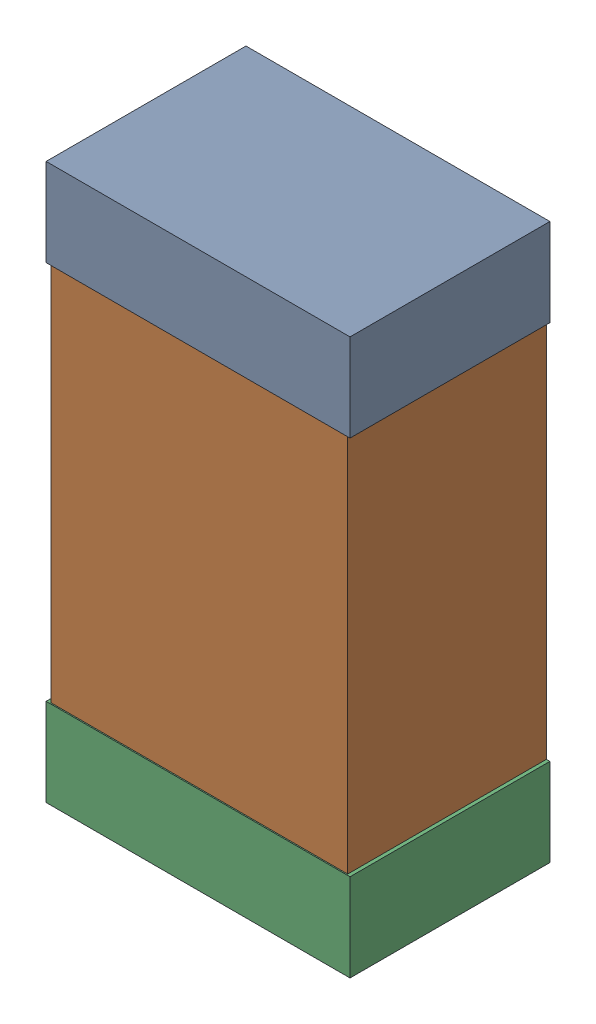
SolidWorks assembly R3_Motor_5Kanaloa_v2.0.0_Loko, configuration Default. Lengths in mm.
Overall size (1.3 2.38 0.85).
6 component instances, 2 part files, 0 mates.
Components (placement in the parent):
- 330415056_1-1: 330415056_1 [Default] at (64.2358 75.9554 0) size (1.3 0.38 0.85)
  - Extruded_29-1: Extruded_29 [Default] at origin size (1.3 0.38 0.85)
- 334787376_1-1: 334787376_1 [Default] at (64.2358 74.9554 0) size (1.27 2.2 0.85)
  - Extruded_30-1: Extruded_30 [Default] at origin size (1.27 2.2 0.85)
- 330415056_1-2: 330415056_1 [Default] at (64.2358 73.9554 0) size (1.3 0.38 0.85)
  - Extruded_29-1: Extruded_29 [Default] at origin size (1.3 0.38 0.85)
